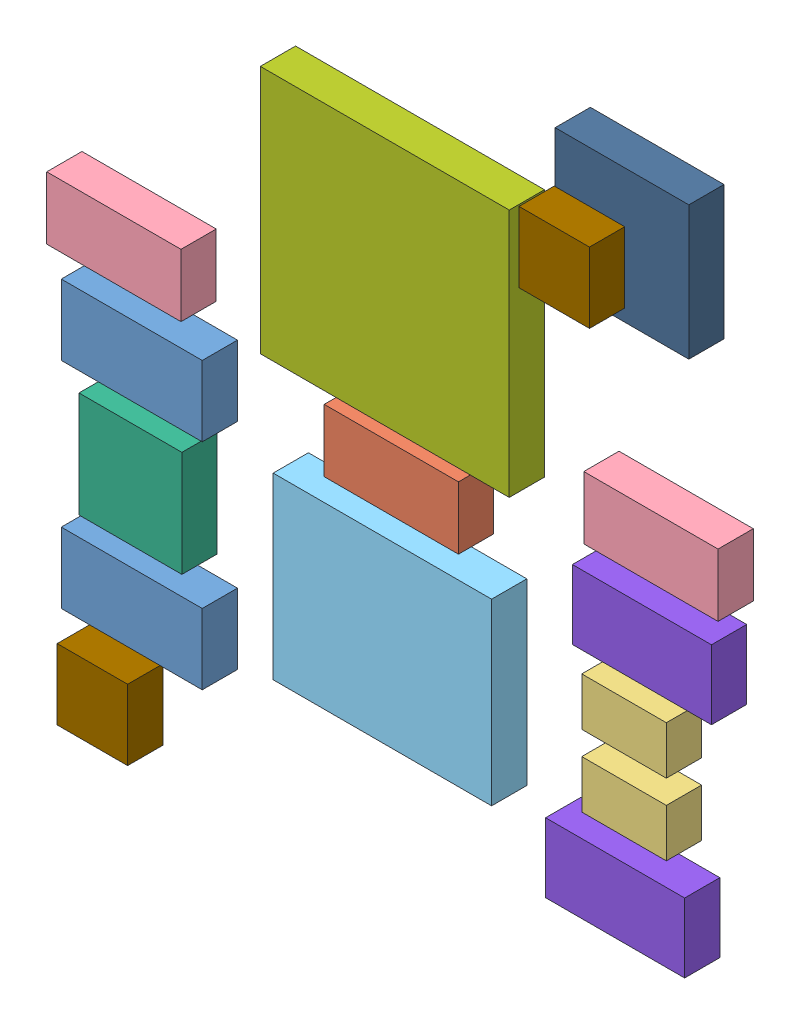
SolidWorks assembly adafruit_max31855 v2, configuration Default. Lengths in mm.
Overall size (20.33 22.86 3.6).
16 component instances, 11 part files, 0 mates.
Components (placement in the parent):
- adafruit_max31855 v2-1: adafruit_max31855 v2 [Default] at origin size (20.33 22.86 1.6)
- C0805K_10UF-1: C0805K_10UF [Default] at (3.048 13.462 1.6) x (-1 0 0) z (0 0 1) size (4 2 1)
- C0805K_10UF-2: C0805K_10UF [Default] at (3.048 7.366 1.6) x (-1 0 0) z (0 0 1) size (4 2 1)
- _0805_0_01_F-1: _0805_0_01_F [Default] at (10.414 14.224 1.6) size (3.81 1.78 1)
- SOD323F_1N4148-1: SOD323F_1N4148 [Default] at (17.018 9.398 1.6) size (2.4 1.36 1)
- SOD323F_1N4148-2: SOD323F_1N4148 [Default] at (17.018 11.43 1.6) size (2.4 1.36 1)
- _0805_FERRITE-1: _0805_FERRITE [Default] at (2.54 16.002 1.6) size (3.81 1.78 1)
- _0805_FERRITE-2: _0805_FERRITE [Default] at (17.78 16.256 1.6) x (-1 0 0) z (0 0 1) size (3.81 1.78 1)
- SO08_MAX31855-1: SO08_MAX31855 [Default] at (10.16 10.16 1.6) x (0 -1 0) z (0 0 1) size (5.08 6.2 1)
- SOT235L_LP298XS-1: SOT235L_LP298XS [Default] at (3.048 10.414 1.6) x (-1 0 0) z (0 0 1) size (2.92 3 1)
- 1X23_5MM_1X23_5MM-1: 1X23_5MM_1X23_5MM [Default] at (10.16 19.05 1.6) size (7.06 7.06 1)
- R0805_10K-1: R0805_10K [Default] at (16.764 7.112 1.6) x (-1 0 0) z (0 0 1) size (3.95 1.97 1)
- R0805_10K-2: R0805_10K [Default] at (17.526 13.716 1.6) x (-1 0 0) z (0 0 1) size (3.95 1.97 1)
- FIDUCIAL_1MM_FIDUCIAL-1: FIDUCIAL_1MM_FIDUCIAL [Default] at (15.0368 21.7424 1.6) size (2 2 1)
- FIDUCIAL_1MM_FIDUCIAL-2: FIDUCIAL_1MM_FIDUCIAL [Default] at (1.9304 4.445 1.6) size (2 2 1)
- ADAFRUIT_3_5MM_U_6_ADAFRUIT_3_5MM-1: ADAFRUIT_3_5MM_U_6_ADAFRUIT_3_5MM [Default] at (16.256 18.796 0) x (-1 0 0) z (0 0 -1) size (3.79 3.79 1)
